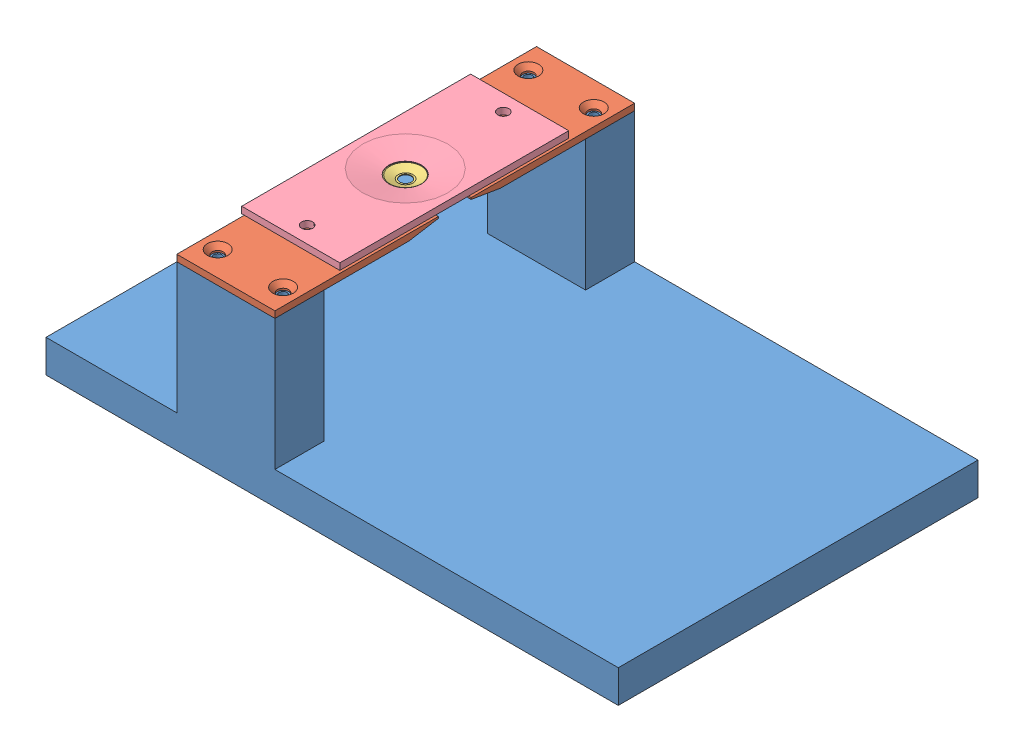
SolidWorks assembly Assem1_v1, configuration Default. Lengths in mm.
Overall size (175 54.62 110).
4 component instances, 4 part files, 2 mates.
Components (placement in the parent):
- Stereotax_base_v1-2: Stereotax_base_v1 [Default] at origin size (175 50 110)
- Original_holderbottom-1: Original_holderbottom [Default] at (55 52 -55) x (0 0 -1) z (-1 0 0) size (110 2 30)
- Original_headplate-1: Original_headplate [Default<As Machined>] at (54.8505 51.6378 -55.1162) x (0.943538 0 0.331264) z (-0.331264 0 0.943538) size (11 1.2 11)
- Original_holdertop-1: Original_holdertop [Default] at (54.8279 52.6153 -55.0244) x (0 0 1) z (-1 0 0) size (70 2 30)
Mates (geometry in assembly coordinates):
- Coincident2: coincident anti-aligned: plane of Stereotax_base_v1-2 through (40 50 -95) normal (0 1 0); plane of Original_holderbottom-1 through (40 50 0) normal (0 -1 0)
- Concentric3: concentric aligned: circle of Stereotax_base_v1-2; circle of Original_holderbottom-1
